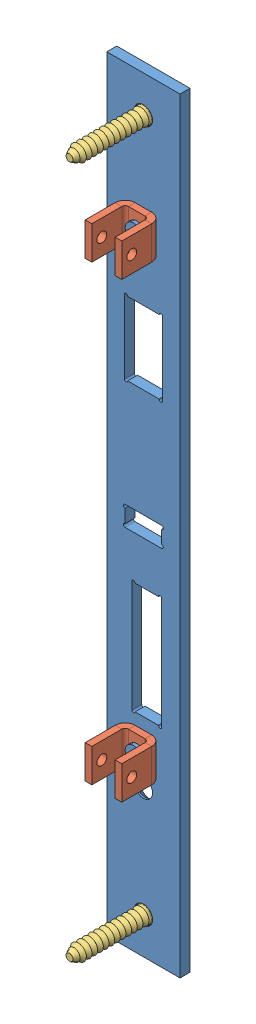
SolidWorks assembly tetiere, configuration Défaut. Lengths in mm.
Overall size (22 230 25.2).
5 component instances, 3 part files, 8 mates.
Components (placement in the parent):
- tetiere-1: tetiere [Défaut] at (-47.7834 3.4752 0) size (22 230 6)
- Pièce37-1: Pièce37 [Défaut] at (-8.0012 83.4752 -19.368) x (1 0 0) z (0 -1 0) size (11 12 10)
- Pièce37-2: Pièce37 [Défaut] at (-8.0012 -52.5248 -19.368) x (1 0 0) z (0 -1 0) size (11 12 10)
- vis F90 M5-25-1: vis F90 M5-25 [PreviewCfg] at (-47.7834 107.4752 -1.3) x (0 0 1) z (-1 0 0) size (25 9.3 9.3)
- vis F90 M5-25-2: vis F90 M5-25 [PreviewCfg] at (-47.7834 -100.5248 -1.3) x (0 0 1) z (-1 0 0) size (25 9.3 9.3)
Mates (geometry in assembly coordinates):
- Coïncidente17: coincident anti-aligned: plane of tetiere-1 through (-58.7834 -111.5248 1.5) normal (0 0 1); plane of Pièce37-1 through (-53.2834 73.4752 1.5) normal (0 0 -1)
- Coaxiale5: concentric anti-aligned: cylinder of tetiere-1 through (-47.7834 78.4752 4.5) axis (0 0 -1) radius 2.5; cylinder of Pièce37-1 through (-47.7834 78.4752 1.5) axis (0 0 1) radius 2.5
- Parallèle1: parallel aligned: plane of tetiere-1 through (-36.7834 118.4752 1.5) normal (1 0 0); plane of Pièce37-1 through (-42.2834 73.4752 1.5) normal (1 0 0)
- Coaxiale6: concentric anti-aligned: cylinder of tetiere-1 through (-47.7834 -57.5248 4.5) axis (0 0 -1) radius 2.5; cylinder of Pièce37-2 through (-47.7834 -57.5248 1.5) axis (0 0 1) radius 2.5
- Coïncidente21: coincident: plane of tetiere-1 through (-58.7834 -111.5248 1.5) normal (0 0 1); moEndPointRef_w of Pièce37-2
- Parallèle2: parallel aligned: plane of tetiere-1 through (-36.7834 118.4752 1.5) normal (1 0 0); plane of Pièce37-2 through (-42.2834 -62.5248 1.5) normal (1 0 0)
- Coïncidente56: coincident aligned: cone of vis F90 M5-25-1 through (-47.7834 107.4752 -0.95) axis (0 0 1); cone of tetiere-1 through (-47.7834 107.4752 -1.5) axis (0 0 1)
- Parallèle7: parallel aligned: plane of tetiere-1 through (-58.7834 118.4752 1.5) normal (-1 0 0); plane of vis F90 M5-25-1 through (-47.2834 107.4752 1.2125) normal (-1 0 0)
